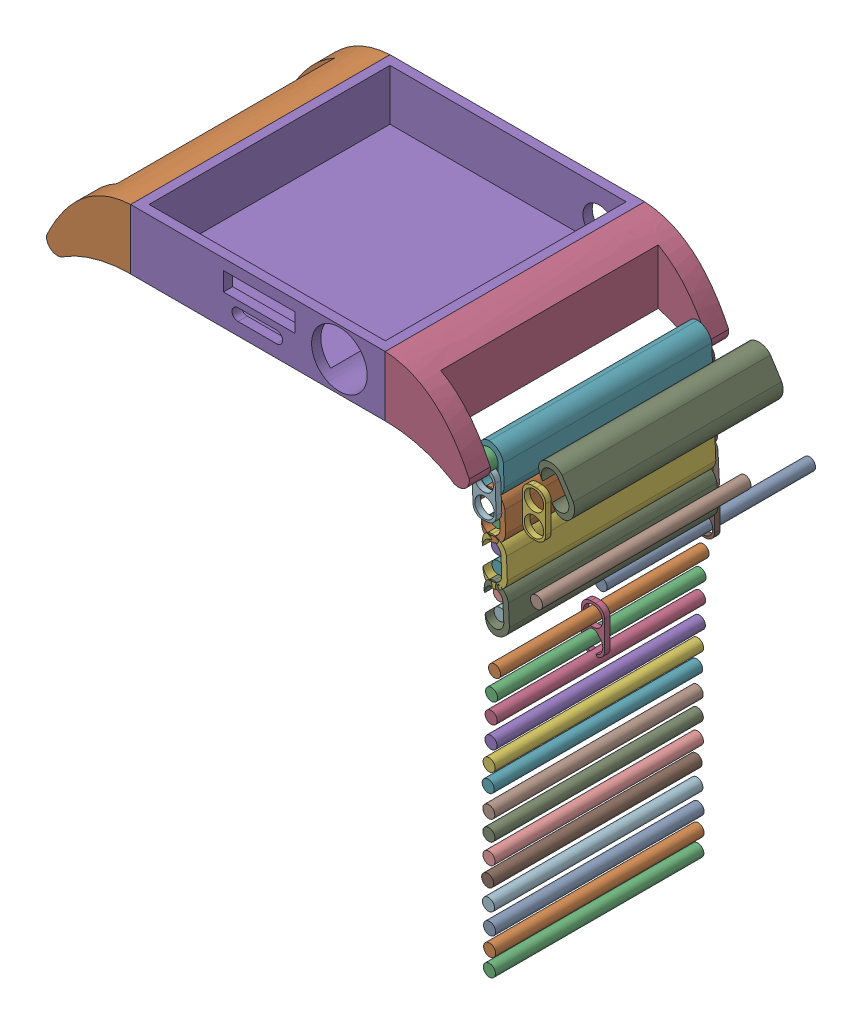
SolidWorks assembly prototype, configuration Default. Lengths in mm.
Overall size (126.98 122.14 91.01).
36 component instances, 4 part files, 33 mates.
Components (placement in the parent):
- Main Base-1: Main Base [Default] at (0.0629 0.1071 -0.106) size (91.28 17.47 56)
- stick spacers-1: stick spacers [Default] at (56.1532 -4.5517 23.1799) size (5.01 9.93 1.2)
- sticks connector-1: sticks connector [Default] at (45.4538 -3.8047 21.4204) x (0 0 1) z (-0.999324 -0.036763 0) size (45 10.1 5.28)
- cordon singlular sticks-1: cordon singlular sticks [Default] at (77.2336 -0.3875 -0.0686) size (2.6 2.6 45)
- sticks connector-4: sticks connector [Default] at (77.6779 18.2988 39.6663) x (0 0 1) z (-0.842844 -0.538158 0) size (45 10.1 5.28)
- cordon singlular sticks-3: cordon singlular sticks [Default] at (43.5234 -5.7009 -24.7796) x (0.996628 -0.082051 0) z (0 0 1) size (2.6 2.6 45)
- stick spacers-3: stick spacers [Default] at (43.6137 -8.0772 -24.7796) x (0.999279 0.037964 0) z (0 0 1) size (5.01 9.93 1.2)
- stick spacers-4: stick spacers [Default] at (43.6137 -8.0772 21.4204) x (0.999279 0.037964 0) z (0 0 1) size (5.01 9.93 1.2)
- cordon singlular sticks-4: cordon singlular sticks [Default] at (43.7095 -10.5996 -24.7796) x (-0.470509 -0.882395 0) z (0 0 1) size (2.6 2.6 45)
- sticks connector-5: sticks connector [Default] at (45.7784 -12.3435 21.4204) x (0 0 1) z (-0.999227 -0.039302 0) size (45 10.1 5.28)
- cordon singlular sticks-5: cordon singlular sticks [Default] at (43.8529 -14.2446 -24.7796) x (-0.276424 -0.961036 0) z (0 0 1) size (2.6 2.6 45)
- stick spacers-5: stick spacers [Default] at (43.9579 -16.6204 -23.5796) x (-0.999025 -0.044155 0) z (0 0 -1) size (5.01 9.93 1.2)
- cordon singlular sticks-6: cordon singlular sticks [Default] at (44.0694 -19.142 -24.7796) x (-0.794992 -0.60662 0) z (0 0 1) size (2.6 2.6 45)
- sticks connector-6: sticks connector [Default] at (46.1409 -20.8829 21.4204) x (0 0 1) z (-0.999167 -0.040804 0) size (45 10.1 5.28)
- cordon singlular sticks-7: cordon singlular sticks [Default] at (44.2182 -22.7869 -24.7796) x (-0.794837 -0.606823 0) z (0 0 1) size (2.6 2.6 45)
- stick spacers-7: stick spacers [Default] at (44.3496 -25.1613 -23.5796) x (-0.998473 -0.055251 0) z (0 0 -1) size (5.01 9.93 1.2)
- sticks connector-7: sticks connector [Default] at (46.5744 -29.4058 21.4204) x (0 0 1) z (-0.998809 -0.048798 0) size (45 10.1 5.28)
- cordon singlular sticks-8: cordon singlular sticks [Default] at (44.4891 -27.6816 -24.7796) x (-0.794854 -0.606801 0) z (0 0 1) size (2.6 2.6 45)
- stick spacers-8: stick spacers [Default] at (44.6729 -33.7032 -24.7796) x (0.999997 0.002465 0) z (0 0 1) size (5.01 9.93 1.2)
- cordon singlular sticks-9: cordon singlular sticks [Default] at (44.6671 -31.3251 -24.7796) x (-0.935269 0.353937 0) z (0 0 1) size (2.6 2.6 45)
- cordon singlular sticks-10: cordon singlular sticks [Default] at (45.1557 -36.0417 -46.0796) x (-0.935269 0.353937 0) z (0 0 1) size (2.6 2.6 45)
- cordon singlular sticks-11: cordon singlular sticks [Default] at (44.6765 -41.2871 -23.5796) x (-0.935269 0.353937 0) z (0 0 1) size (2.6 2.6 45)
- cordon singlular sticks-12: cordon singlular sticks [Default] at (44.5623 -45.4688 -23.0398) x (-0.935269 0.353937 0) z (0 0 1) size (2.6 2.6 45)
- cordon singlular sticks-13: cordon singlular sticks [Default] at (44.4709 -49.8081 -23.0398) x (-0.935269 0.353937 0) z (0 0 1) size (2.6 2.6 45)
- cordon singlular sticks-14: cordon singlular sticks [Default] at (44.4288 -54.493 -23.0398) x (-0.935269 0.353937 0) z (0 0 1) size (2.6 2.6 45)
- cordon singlular sticks-15: cordon singlular sticks [Default] at (44.0401 -58.8803 -23.0398) x (-0.935269 0.353937 0) z (0 0 1) size (2.6 2.6 45)
- cordon singlular sticks-16: cordon singlular sticks [Default] at (43.838 -62.9469 -23.0398) x (-0.935269 0.353937 0) z (0 0 1) size (2.6 2.6 45)
- cordon singlular sticks-17: cordon singlular sticks [Default] at (43.9637 -67.665 -23.0398) x (-0.935269 0.353937 0) z (0 0 1) size (2.6 2.6 45)
- cordon singlular sticks-18: cordon singlular sticks [Default] at (43.9761 -71.9437 -23.0398) x (-0.935269 0.353937 0) z (0 0 1) size (2.6 2.6 45)
- cordon singlular sticks-19: cordon singlular sticks [Default] at (44.0044 -76.3402 -23.0398) x (-0.935269 0.353937 0) z (0 0 1) size (2.6 2.6 45)
- cordon singlular sticks-20: cordon singlular sticks [Default] at (43.7266 -80.6331 -23.0398) x (-0.935269 0.353937 0) z (0 0 1) size (2.6 2.6 45)
- cordon singlular sticks-21: cordon singlular sticks [Default] at (43.8901 -85.0476 -23.0398) x (-0.935269 0.353937 0) z (0 0 1) size (2.6 2.6 45)
- cordon singlular sticks-22: cordon singlular sticks [Default] at (44.1353 -89.4213 -23.0398) x (-0.935269 0.353937 0) z (0 0 1) size (2.6 2.6 45)
- cordon singlular sticks-23: cordon singlular sticks [Default] at (44.148 -93.4419 -23.0398) x (-0.935269 0.353937 0) z (0 0 1) size (2.6 2.6 45)
- cordon singlular sticks-24: cordon singlular sticks [Default] at (44.0892 -97.2632 -23.0398) x (-0.935269 0.353937 0) z (0 0 1) size (2.6 2.6 45)
- stick spacers-9: stick spacers [Default] at (44.5328 -44.1365 -1.1741) x (0.999997 0.002465 0) z (0 0 1) size (5.01 9.93 1.2)
Mates (geometry in assembly coordinates):
- Concentric2: concentric aligned: circle of Main Base-1; circle of sticks connector-1
- Concentric3: concentric anti-aligned: circle of sticks connector-1; circle of cordon singlular sticks-3
- Concentric4: concentric aligned: circle of cordon singlular sticks-3; circle of stick spacers-3
- Coincident6: coincident anti-aligned: plane of sticks connector-1 through (45.4538 -3.8047 -23.5796) normal (0 0 -1); plane of stick spacers-3 through (43.6137 -8.0772 -23.5796) normal (0 0 1)
- Coincident7: coincident aligned: plane of cordon singlular sticks-3 through (43.5234 -5.7009 -24.7796) normal (0 0 -1); plane of stick spacers-3 through (43.6137 -8.0772 -24.7796) normal (0 0 -1)
- Coincident8: coincident anti-aligned: plane of Main Base-1 through (34.9913 11.1071 -23.5796) normal (0 0 1); plane of sticks connector-1 through (45.4538 -3.8047 -23.5796) normal (0 0 -1)
- Concentric5: concentric anti-aligned: circle of sticks connector-1; circle of stick spacers-4
- Coincident10: coincident anti-aligned: plane of sticks connector-1 through (45.4538 -3.8047 21.4204) normal (0 0 1); plane of stick spacers-4 through (43.6137 -8.0772 21.4204) normal (0 0 -1)
- Concentric6: concentric aligned: circle of stick spacers-3; circle of cordon singlular sticks-4
- Concentric7: concentric aligned: circle of stick spacers-4; circle of cordon singlular sticks-4
- Coincident11: coincident aligned: plane of stick spacers-3 through (43.6137 -8.0772 -24.7796) normal (0 0 -1); plane of cordon singlular sticks-4 through (43.7095 -10.5996 -24.7796) normal (0 0 -1)
- Concentric8: concentric aligned: circle of cordon singlular sticks-4; circle of sticks connector-5
- Coincident12: coincident anti-aligned: plane of stick spacers-3 through (43.6137 -8.0772 -23.5796) normal (0 0 1); plane of sticks connector-5 through (45.7784 -12.3435 -23.5796) normal (0 0 -1)
- Concentric9: concentric anti-aligned: circle of sticks connector-5; circle of cordon singlular sticks-5
- Coincident13: coincident aligned: plane of cordon singlular sticks-4 through (43.7095 -10.5996 -24.7796) normal (0 0 -1); plane of cordon singlular sticks-5 through (43.8529 -14.2446 -24.7796) normal (0 0 -1)
- Concentric10: concentric anti-aligned: circle of cordon singlular sticks-5; circle of stick spacers-5
- Coincident15: coincident aligned: plane of stick spacers-3 through (43.6137 -8.0772 -24.7796) normal (0 0 -1); plane of stick spacers-5 through (43.9579 -16.6204 -24.7796) normal (0 0 -1)
- Concentric11: concentric anti-aligned: circle of stick spacers-5; circle of cordon singlular sticks-6
- Coincident17: coincident aligned: plane of stick spacers-5 through (43.9579 -16.6204 -24.7796) normal (0 0 -1); plane of cordon singlular sticks-6 through (44.0694 -19.142 -24.7796) normal (0 0 -1)
- Concentric12: concentric aligned: circle of cordon singlular sticks-6; circle of sticks connector-6
- Coincident18: coincident aligned: plane of sticks connector-5 through (45.7784 -12.3435 -23.5796) normal (0 0 -1); plane of sticks connector-6 through (46.1409 -20.8829 -23.5796) normal (0 0 -1)
- Concentric13: concentric anti-aligned: circle of sticks connector-6; circle of cordon singlular sticks-7
- Coincident19: coincident aligned: plane of cordon singlular sticks-6 through (44.0694 -19.142 -24.7796) normal (0 0 -1); plane of cordon singlular sticks-7 through (44.2182 -22.7869 -24.7796) normal (0 0 -1)
- Coincident20: coincident aligned: plane of stick spacers-5 through (43.9579 -16.6204 -24.7796) normal (0 0 -1); plane of stick spacers-7 through (44.3496 -25.1613 -24.7796) normal (0 0 -1)
- Concentric14: concentric anti-aligned: circle of cordon singlular sticks-7; circle of stick spacers-7
- Concentric15: concentric anti-aligned: circle of stick spacers-7; circle of cordon singlular sticks-8
- Concentric16: concentric aligned: circle of sticks connector-7; circle of cordon singlular sticks-8
- Coincident22: coincident aligned: plane of cordon singlular sticks-7 through (44.2182 -22.7869 -24.7796) normal (0 0 -1); plane of cordon singlular sticks-8 through (44.4891 -27.6816 -24.7796) normal (0 0 -1)
- Coincident23: coincident aligned: plane of sticks connector-6 through (46.1409 -20.8829 -23.5796) normal (0 0 -1); plane of sticks connector-7 through (46.5744 -29.4058 -23.5796) normal (0 0 -1)
- Coincident25: coincident aligned: plane of cordon singlular sticks-8 through (44.4891 -27.6816 -24.7796) normal (0 0 -1); plane of cordon singlular sticks-9 through (44.6671 -31.3251 -24.7796) normal (0 0 -1)
- Concentric18: concentric aligned: circle of stick spacers-8; circle of cordon singlular sticks-9
- Concentric19: concentric anti-aligned: circle of sticks connector-7; circle of cordon singlular sticks-9
- Coincident26: coincident aligned: plane of stick spacers-8 through (44.6729 -33.7032 -24.7796) normal (0 0 -1); plane of cordon singlular sticks-9 through (44.6671 -31.3251 -24.7796) normal (0 0 -1)
